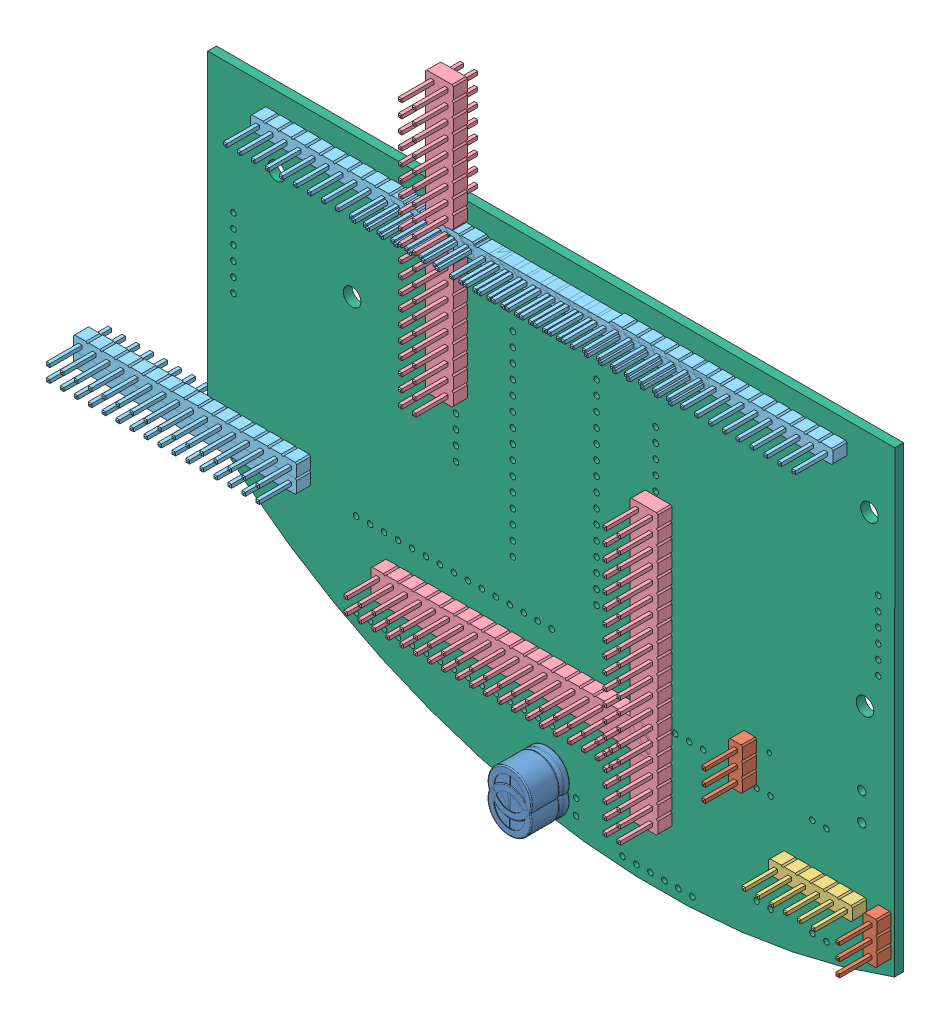
SolidWorks assembly mike_pcb_motors_new, configuration Default. Lengths in mm.
Overall size (146.87 110.73 11.54).
30 component instances, 6 part files, 0 mates.
Components (placement in the parent):
- mike_pcb_motors_new.step-1: mike_pcb_motors_new.step [Default] at origin size (146.87 110.73 11.54)
  - PinHeader_1x03_P2.54mm_Vertical.step-1: PinHeader_1x03_P2.54mm_Vertical.step [Default] at (128.44 -215.85 1.65) x (0 1 0) z (0 0 1) size (10.06 10.93 9)
    - SOLID.step-1: SOLID.step [Default] at origin size (10.06 10.93 9)
  - PinHeader_1x03_P2.54mm_Vertical.step-2: PinHeader_1x03_P2.54mm_Vertical.step [Default] at (128.42 -218.63 1.65) x (0 1 0) z (0 0 1) size (10.06 10.93 9)
    - SOLID.step-1: SOLID.step [Default] at origin size (10.06 10.93 9)
  - C_Radial_D8.0mm_H7.0mm_P3.50mm.step-1: C_Radial_D8.0mm_H7.0mm_P3.50mm.step [Default] at (189.58 -211.46 1.65) x (-1 0 0) z (0 0 1) size (2.54 7.62 11.54)
    - SOLID-0.step-1: SOLID-0.step [Default] at origin size (2.54 7.62 11.54)
  - C_Radial_D8.0mm_H7.0mm_P3.50mm.step-2: C_Radial_D8.0mm_H7.0mm_P3.50mm.step [Default] at (165.13 -191.13 1.65) size (2.54 7.62 11.54)
    - SOLID-0.step-1: SOLID-0.step [Default] at origin size (2.54 7.62 11.54)
  - PinHeader_1x08_P2.54mm_Vertical.step-1: PinHeader_1x08_P2.54mm_Vertical.step [Default] at (172.41 -206.44 1.65) x (0 1 0) z (0 0 1) size (2.54 15.24 11.54)
    - SOLID-1.step-1: SOLID-1.step [Default] at origin size (2.54 15.24 11.54)
  - PinHeader_1x11_P2.54mm_Vertical.step-1: PinHeader_1x11_P2.54mm_Vertical.step [Default] at (147.15 -162.24 1.65) size (5.08 50.8 11.54)
    - SOLID-2.step-1: SOLID-2.step [Default] at origin size (5.08 50.8 11.54)
  - PinHeader_1x11_P2.54mm_Vertical.step-2: PinHeader_1x11_P2.54mm_Vertical.step [Default] at (112.49 -161.66 1.65) x (-1 0 0) z (0 0 1) size (5.08 50.8 11.54)
    - SOLID-2.step-1: SOLID-2.step [Default] at origin size (5.08 50.8 11.54)
  - PinHeader_1x11_P2.54mm_Vertical.step-3: PinHeader_1x11_P2.54mm_Vertical.step [Default] at (148.28 -196.695 1.65) x (0 -1 0) z (0 0 1) size (5.08 50.8 11.54)
    - SOLID-2.step-1: SOLID-2.step [Default] at origin size (5.08 50.8 11.54)
  - PinHeader_1x06_P2.54mm_Vertical.step-1: PinHeader_1x06_P2.54mm_Vertical.step [Default] at (181.55 -136.19 1.65) x (0 -1 0) z (0 0 1) size (2.54 40.64 11.54)
    - SOLID-3.step-1: SOLID-3.step [Default] at origin size (2.54 40.64 11.54)
  - PinHeader_1x06_P2.54mm_Vertical.step-2: PinHeader_1x06_P2.54mm_Vertical.step [Default] at (83.99 -189.66 1.65) x (0 -1 0) z (0 0 1) size (2.54 40.64 11.54)
    - SOLID-3.step-1: SOLID-3.step [Default] at origin size (2.54 40.64 11.54)
  - PinHeader_1x06_P2.54mm_Vertical.step-3: PinHeader_1x06_P2.54mm_Vertical.step [Default] at (83.99 -187.16 1.65) x (0 -1 0) z (0 0 1) size (2.54 40.64 11.54)
    - SOLID-3.step-1: SOLID-3.step [Default] at origin size (2.54 40.64 11.54)
  - PinHeader_1x06_P2.54mm_Vertical.step-4: PinHeader_1x06_P2.54mm_Vertical.step [Default] at (116.24 -136.35 1.65) x (0 -1 0) z (0 0 1) size (2.54 40.64 11.54)
    - SOLID-3.step-1: SOLID-3.step [Default] at origin size (2.54 40.64 11.54)
  - PinHeader_1x06_P2.54mm_Vertical.step-5: PinHeader_1x06_P2.54mm_Vertical.step [Default] at (139.57 -136.66 1.65) x (0 -1 0) z (0 0 1) size (2.54 40.64 11.54)
    - SOLID-3.step-1: SOLID-3.step [Default] at origin size (2.54 40.64 11.54)
  - PinHeader_1x06_P2.54mm_Vertical.step-6: PinHeader_1x06_P2.54mm_Vertical.step [Default] at (159.03 -136.66 1.65) x (0 -1 0) z (0 0 1) size (2.54 40.64 11.54)
    - SOLID-3.step-1: SOLID-3.step [Default] at origin size (2.54 40.64 11.54)
  - COMPOUND.step-1: COMPOUND.step [Default] at origin size (125 91.12 1.6)
